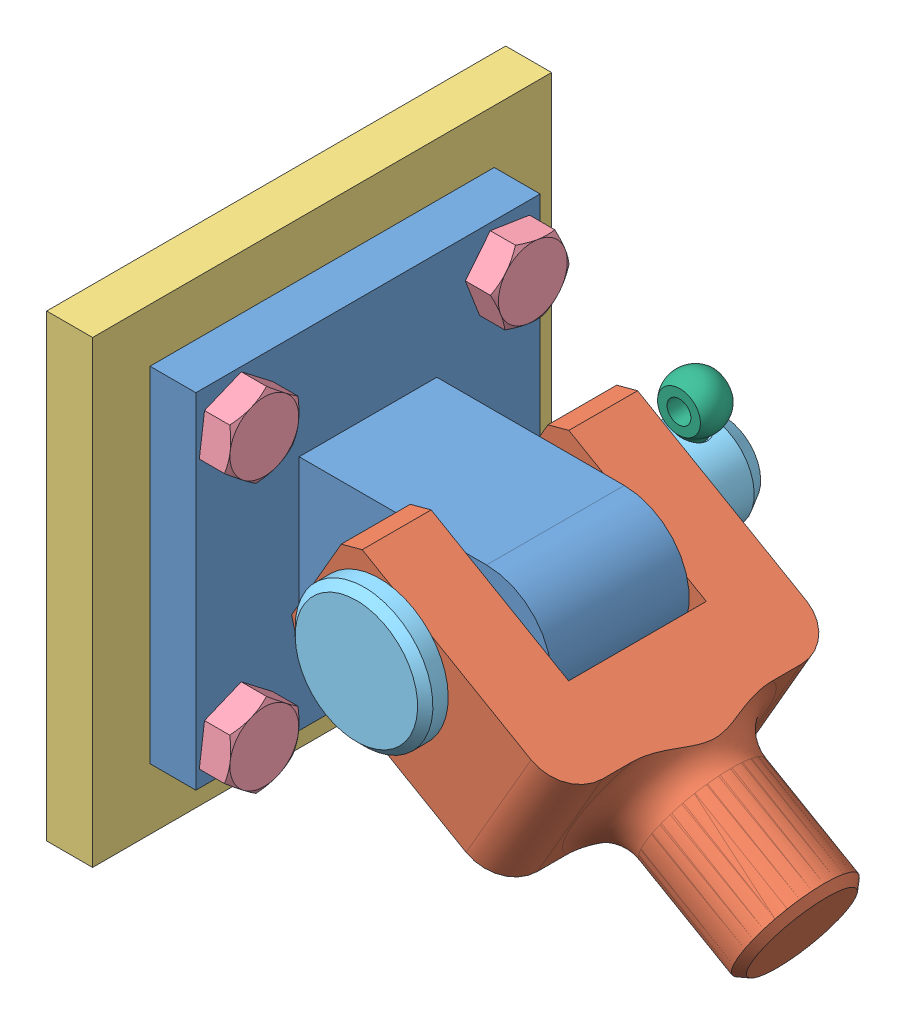
SolidWorks assembly złożenie tego gówna, configuration Domyślna. Lengths in mm.
Overall size (161.98 120 120).
17 component instances, 8 part files, 25 mates.
Components (placement in the parent):
- przyklad-1: przyklad [Domyślna] at origin size (78 90 90)
- widełki-2: widełki [Domyślna] at (-826.6659 546.4277 -8.7445) x (0 0 -1) z (0.866025 -0.5 0) size (72 34 105)
- podstawka-1: podstawka [Domyślna] at (-849.5535 565.8049 -10.5174) x (0 0 1) z (-1 0 0) size (120 120 12)
- hex head structural bolt_din-27: hex head structural bolt_din [DIN 7990 - M12 x 40-WC] at (-829.5535 591.2203 35.1005) x (-1 0 0) z (0 -0.924225 -0.381849) size (48 20.78 18)
- hex head structural bolt_din-28: hex head structural bolt_din [DIN 7990 - M12 x 40-WC] at (-829.5535 591.2203 -35.1005) x (-1 0 0) z (0 0.359231 -0.933249) size (48 20.78 18)
- hex head structural bolt_din-29: hex head structural bolt_din [DIN 7990 - M12 x 40-WC] at (-829.5535 521.0193 35.1005) x (-1 0 0) z (0 -0.924225 -0.381849) size (48 20.78 18)
- hex head structural bolt_din-30: hex head structural bolt_din [DIN 7990 - M12 x 40-WC] at (-829.5535 521.0193 -35.1005) x (-1 0 0) z (0 -0.924225 -0.381849) size (48 20.78 18)
- clevis pin headed_din-3: clevis pin headed_din [DIN EN 22341 - B - 24 x 90 x 6.3 - St] at (-798.5535 557.1198 42.0263) x (0 0 -1) z (0.088123 0.99611 0) size (96 36 36)
- eyebolt_din-4: eyebolt_din [DIN 444 - LA M6 x 35 --- 18N] at (-796.9278 575.4971 -44.9737) x (-0.088123 -0.99611 0) z (0.044484 -0.003935 0.999002) size (42 14 9)
- hex nut high strength_din-13: hex nut high strength_din [Hexagon Nut DIN 6915 - M12 - N] at (-864.0535 591.2203 -35.1005) x (0 0.123462 -0.992349) z (1 0 0) size (22 25.4 10)
- hex nut high strength_din-14: hex nut high strength_din [Hexagon Nut DIN 6915 - M12 - N] at (-874.0535 521.0193 -35.1005) x (0 0 1) z (-1 0 0) size (22 25.4 10)
- hex nut high strength_din-15: hex nut high strength_din [Hexagon Nut DIN 6915 - M12 - N] at (-864.0535 521.0193 35.1005) x (0 0 -1) z (1 0 0) size (22 25.4 10)
- hex nut high strength_din-16: hex nut high strength_din [Hexagon Nut DIN 6915 - M12 - N] at (-874.0535 591.2203 35.1005) x (0 -0.189642 0.981853) z (-1 0 0) size (22 25.4 10)
- plain washer hardened grade a_din-1: plain washer hardened grade a_din [Washer DIN 125 - A 13 - 300HV] at (-864.0535 521.0193 -35.1005) x (-1 0 0) z (0 -0.924225 -0.381849) size (2.5 24 24)
- plain washer hardened grade a_din-2: plain washer hardened grade a_din [Washer DIN 125 - A 13 - 300HV] at (-864.0535 591.2203 -35.1005) x (-1 0 0) z (0 -0.924225 -0.381849) size (2.5 24 24)
- plain washer hardened grade a_din-3: plain washer hardened grade a_din [Washer DIN 125 - A 13 - 300HV] at (-864.0535 591.2203 35.1005) x (-1 0 0) z (0 -0.924225 -0.381849) size (2.5 24 24)
- plain washer hardened grade a_din-4: plain washer hardened grade a_din [Washer DIN 125 - A 13 - 300HV] at (-864.0535 521.0193 35.1005) x (-1 0 0) z (0 -0.924225 -0.381849) size (2.5 24 24)
Mates (geometry in assembly coordinates):
- Hinge1: hinge = 2.094395 rad anti-aligned: cylinder of przyklad-1 through (-798.5535 557.1198 -18) axis (0 0 1) radius 12; cylinder of widełki-2 through (-798.5535 557.1198 -36.9737) axis (0 0 1) radius 12; plane of przyklad-1 through (0 0 18) normal (0 0 1); plane of widełki-2 through (-784.1039 529.1474 18) normal (0 0 -1); plane of widełki-2 through (-724.0754 514.1198 0.0263) normal (0.866025 -0.5 0); plane of przyklad-1 through (0 574.1198 -18) normal (0 1 0)
- Coincident9: coincident anti-aligned: plane of przyklad-1 through (-837.5535 0 -45) normal (1 0 0); plane of hex head structural bolt_din-28 through (-837.5535 600.9189 -31.3673) normal (-1 0 0)
- Coincident10: coincident aligned: plane of przyklad-1 through (-837.5535 0 -45) normal (1 0 0); circle of hex head structural bolt_din-30
- Coincident11: coincident aligned: plane of przyklad-1 through (-837.5535 0 -45) normal (1 0 0); circle of hex head structural bolt_din-27
- Coincident12: coincident anti-aligned: plane of przyklad-1 through (-837.5535 0 -45) normal (1 0 0); plane of hex head structural bolt_din-29 through (-837.5535 524.9876 25.4957) normal (-1 0 0)
- Concentric11: concentric aligned: cylinder of widełki-2 through (-798.5535 557.1198 -36.9737) axis (0 0 1) radius 12; cylinder of clevis pin headed_din-3 through (-798.5535 557.1198 42.0263) axis (0 0 1) radius 18
- Hinge3: hinge anti-aligned: cylinder of clevis pin headed_din-3 through (-798.5535 557.1198 42.0263) axis (0 0 1) radius 12; cylinder of widełki-2 through (-798.5535 557.1198 -36.9737) axis (0 0 1) radius 12; plane of widełki-2 through (-767.2164 519.3974 36.0263) normal (0 0 1); plane of clevis pin headed_din-3 through (-816.4835 558.706 36.0263) normal (0 0 -1)
- Concentric12: concentric aligned: cylinder of clevis pin headed_din-3 through (-799.611 545.1665 -44.9737) axis (0.088123 0.99611 0) radius 3.15; cylinder of eyebolt_din-4 through (-794.1299 607.1236 -44.9737) axis (0.088123 0.99611 0) radius 3
- Concentric13: concentric anti-aligned: cylinder of hex head structural bolt_din-30 through (-829.5535 521.0193 -35.1005) axis (1 0 0) radius 6; cylinder of hex nut high strength_din-14 through (-849.016 521.0193 -35.1005) axis (-1 0 0) radius 6
- Concentric14: concentric anti-aligned: cylinder of hex head structural bolt_din-27 through (-829.5535 591.2203 35.1005) axis (1 0 0) radius 6; cylinder of hex nut high strength_din-16 through (-849.016 591.2203 35.1005) axis (-1 0 0) radius 6
- Concentric15: concentric aligned: cylinder of hex head structural bolt_din-28 through (-829.5535 591.2203 -35.1005) axis (1 0 0) radius 6; cylinder of hex nut high strength_din-13 through (-874.0535 591.2203 -35.1005) axis (1 0 0) radius 5.1
- Concentric16: concentric aligned: cylinder of hex head structural bolt_din-29 through (-829.5535 521.0193 35.1005) axis (1 0 0) radius 6; cylinder of hex nut high strength_din-15 through (-874.0535 521.0193 35.1005) axis (1 0 0) radius 5.1
- Concentric18: concentric aligned: cylinder of hex head structural bolt_din-30 through (-829.5535 521.0193 -35.1005) axis (1 0 0) radius 6; cylinder of plain washer hardened grade a_din-1 through (-829.1285 521.0193 -35.1005) axis (1 0 0) radius 6.5
- Coincident14: coincident anti-aligned: plane of podstawka-1 through (-861.5535 565.8049 -10.5174) normal (-1 0 0); plane of plain washer hardened grade a_din-1 through (-861.5535 525.6015 -46.1912) normal (1 0 0)
- Coincident15: coincident anti-aligned: plane of przyklad-1 through (-849.5535 0 -45) normal (-1 0 0); plane of podstawka-1 through (-849.5535 565.8049 -10.5174) normal (1 0 0)
- Coincident16: coincident anti-aligned: plane of hex nut high strength_din-14 through (-864.0535 521.0193 -57.1005) normal (1 0 0); plane of plain washer hardened grade a_din-1 through (-864.0535 523.5013 -41.108) normal (-1 0 0)
- Concentric19: concentric aligned: cylinder of hex head structural bolt_din-28 through (-829.5535 591.2203 -35.1005) axis (1 0 0) radius 6; cylinder of plain washer hardened grade a_din-2 through (-829.1285 591.2203 -35.1005) axis (1 0 0) radius 6.5
- Concentric20: concentric aligned: cylinder of hex head structural bolt_din-27 through (-829.5535 591.2203 35.1005) axis (1 0 0) radius 6; cylinder of plain washer hardened grade a_din-3 through (-829.1285 591.2203 35.1005) axis (1 0 0) radius 6.5
- Concentric21: concentric aligned: cylinder of hex head structural bolt_din-29 through (-829.5535 521.0193 35.1005) axis (1 0 0) radius 6; cylinder of plain washer hardened grade a_din-4 through (-829.1285 521.0193 35.1005) axis (1 0 0) radius 6.5
- Coincident17: coincident anti-aligned: plane of podstawka-1 through (-861.5535 565.8049 -10.5174) normal (-1 0 0); plane of plain washer hardened grade a_din-2 through (-861.5535 595.8025 -46.1912) normal (1 0 0)
- Coincident18: coincident anti-aligned: plane of podstawka-1 through (-861.5535 565.8049 -10.5174) normal (-1 0 0); plane of plain washer hardened grade a_din-3 through (-861.5535 595.8025 24.0098) normal (1 0 0)
- Coincident19: coincident anti-aligned: plane of podstawka-1 through (-861.5535 565.8049 -10.5174) normal (-1 0 0); plane of plain washer hardened grade a_din-4 through (-861.5535 525.6015 24.0098) normal (1 0 0)
- Coincident20: coincident anti-aligned: plane of hex nut high strength_din-16 through (-864.0535 595.3924 13.4997) normal (1 0 0); plane of plain washer hardened grade a_din-3 through (-864.0535 593.7023 29.093) normal (-1 0 0)
- Coincident21: coincident anti-aligned: plane of hex nut high strength_din-13 through (-864.0535 588.5041 -13.2688) normal (1 0 0); plane of plain washer hardened grade a_din-2 through (-864.0535 593.7023 -41.108) normal (-1 0 0)
- Coincident22: coincident anti-aligned: plane of hex nut high strength_din-15 through (-864.0535 521.0193 57.1005) normal (1 0 0); plane of plain washer hardened grade a_din-4 through (-864.0535 523.5013 29.093) normal (-1 0 0)
